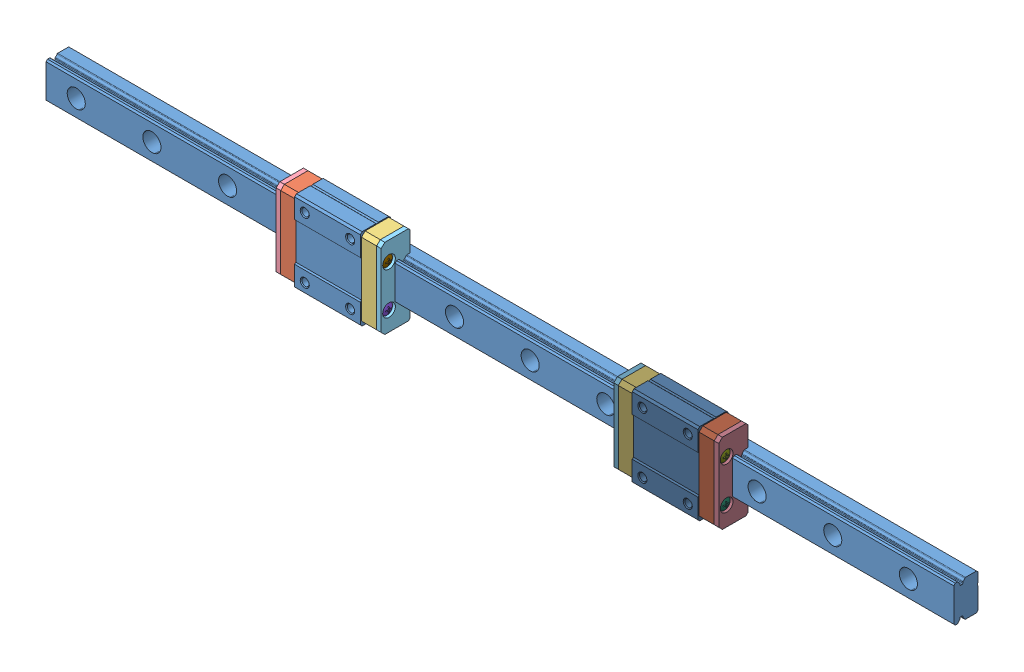
SolidWorks assembly MGN12H2R300ZFC-HiwinCorporation-3D-11-05-2020, configuration Default. Lengths in mm.
Overall size (300 27 13.07).
21 component instances, 19 part files, 4 mates.
Components (placement in the parent):
- MGN12H^MGN12H2R300ZFC-HiwinCorporation-3D-11-05-2020-1: MGN12H^MGN12H2R300ZFC-HiwinCorporation-3D-11-05-2020 [Default] at origin size (34.9 27 10) (virtual)
  - PRODUCT_ID_1-1: PRODUCT_ID_1 [Default] at origin size (21.7 27 10)
  - PRODUCT_ID_2-1: PRODUCT_ID_2 [Default] at origin size (5 26.4 9.6)
  - PRODUCT_ID_3-1: PRODUCT_ID_3 [Default] at origin size (5 26.4 9.6)
  - PRODUCT_ID_4-1: PRODUCT_ID_4 [Default] at origin size (1.5 26.4 9.6)
  - PRODUCT_ID_5-1: PRODUCT_ID_5 [Default] at origin size (1.5 26.4 9.6)
  - PRODUCT_ID_6-1: PRODUCT_ID_6 [Default] at origin size (1.7 4 4)
  - PRODUCT_ID_7-1: PRODUCT_ID_7 [Default] at origin size (1.7 4 4)
  - PRODUCT_ID_8-1: PRODUCT_ID_8 [Default] at origin size (1.7 4 4)
  - PRODUCT_ID_9-1: PRODUCT_ID_9 [Default] at origin size (1.7 4 4)
- MGN12H Block 2^MGN12H2R300ZFC-HiwinCorporation-3D-11-05-2020-1: MGN12H Block 2^MGN12H2R300ZFC-HiwinCorporation-3D-11-05-2020 [Default] at origin size (34.9 27 10) (virtual)
  - PRODUCT_ID_10-1: PRODUCT_ID_10 [Default] at origin size (21.7 27 10)
  - PRODUCT_ID_11-1: PRODUCT_ID_11 [Default] at origin size (5 26.4 9.6)
  - PRODUCT_ID_12-1: PRODUCT_ID_12 [Default] at origin size (5 26.4 9.6)
  - PRODUCT_ID_13-1: PRODUCT_ID_13 [Default] at origin size (1.5 26.4 9.6)
  - PRODUCT_ID_14-1: PRODUCT_ID_14 [Default] at origin size (1.5 26.4 9.6)
  - PRODUCT_ID_15-1: PRODUCT_ID_15 [Default] at origin size (1.7 4 4)
  - PRODUCT_ID_16-1: PRODUCT_ID_16 [Default] at origin size (1.7 4 4)
  - PRODUCT_ID_17-1: PRODUCT_ID_17 [Default] at origin size (1.7 4 4)
  - PRODUCT_ID_18-1: PRODUCT_ID_18 [Default] at origin size (1.7 4 4)
- MGN12 Rail 300-1: MGN12 Rail 300 [Default] at origin size (300 12 8.07)
Mates (geometry in assembly coordinates):
- Coincident1: coincident aligned: plane of MGN12H^MGN12H2R300ZFC-HiwinCorporation-3D-11-05-2020-1 through (0 0 0) normal (0 1 0); plane of MGN12 Rail 300-1 through (0 0 0) normal (0 1 0)
- Coincident2: coincident aligned: plane of MGN12H^MGN12H2R300ZFC-HiwinCorporation-3D-11-05-2020-1 through (0 0 0) normal (0 0 1); plane of MGN12 Rail 300-1 through (0 0 0) normal (0 0 1)
- Coincident3: coincident aligned: plane of MGN12H Block 2^MGN12H2R300ZFC-HiwinCorporation-3D-11-05-2020-1 through (0 0 0) normal (0 0 1); plane of MGN12 Rail 300-1 through (0 0 0) normal (0 0 1)
- Coincident4: coincident aligned: plane of MGN12H Block 2^MGN12H2R300ZFC-HiwinCorporation-3D-11-05-2020-1 through (0 0 0) normal (0 1 0); plane of MGN12 Rail 300-1 through (0 0 0) normal (0 1 0)
